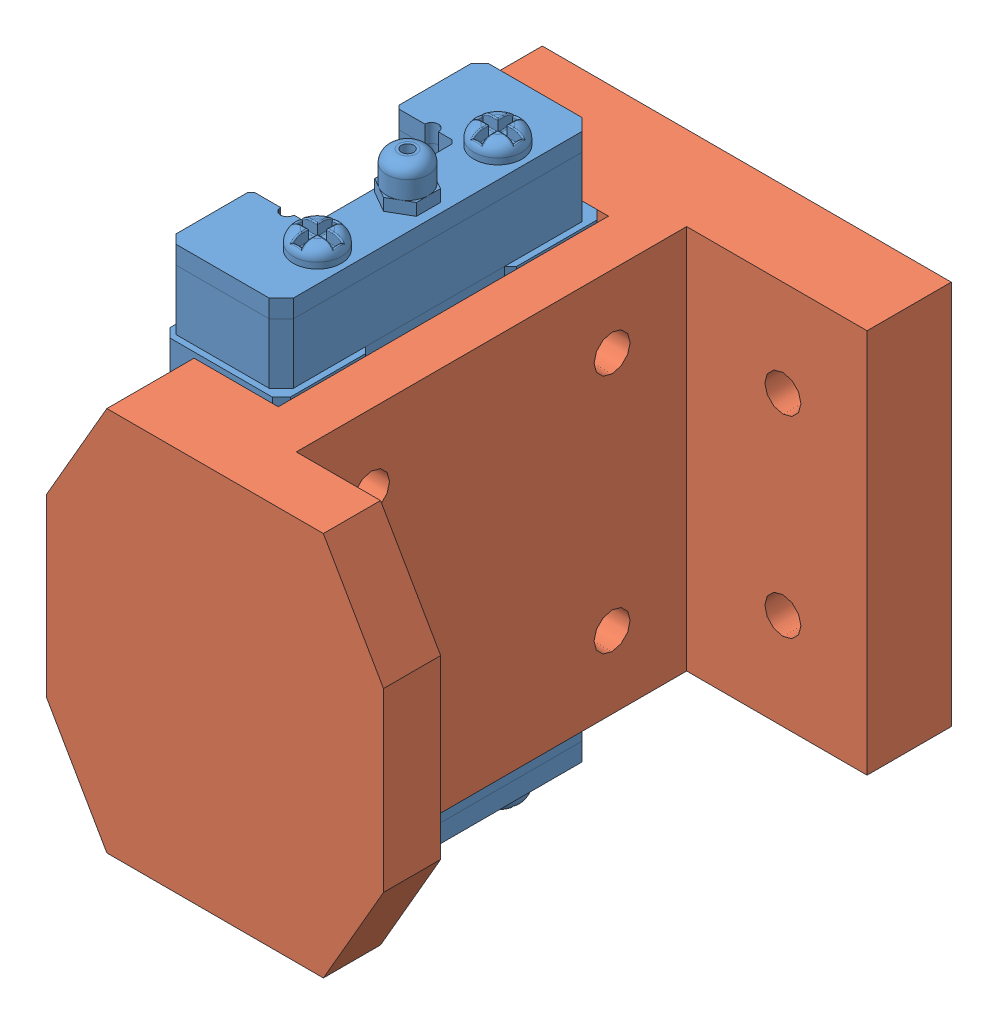
SolidWorks assembly Ползун с зажимом зеркально 2, configuration По умолчанию. Lengths in mm.
Overall size (34 50.47 44.2).
2 component instances, 2 part files, 6 mates.
Components (placement in the parent):
- Ползун-1: Ползун [Default] at (-13 6.5 0) x (0 0 1) z (0 1 0) size (27 10 50.47)
- Тавр обрезаный-2: Тавр обрезаный [По умолчанию] at (0 38.7 -18) x (0 0 1) z (1 0 0) size (44.2 32 34)
Mates (geometry in assembly coordinates):
- Совпадение1: coincident anti-aligned: plane of Ползун-1 through (-7 0 6) normal (0 -1 0); plane of assembly through (0 0 0) normal (0 1 0)
- Совпадение2: coincident aligned: plane of Ползун-1 through (0 38.9 -13.5) normal (1 0 0); plane of assembly through (0 0 0) normal (1 0 0)
- Совпадение3: coincident anti-aligned: plane of Ползун-1; plane of assembly through (0 0 0) normal (0 0 1)
- Concentric6: concentric: cylinder of Ползун-1 through (0 12.7 10) axis (1 0 0) radius 1.25; cylinder of Тавр обрезаный-2 through (27.0125 12.7 10) axis (-1 0 0) radius 1.5
- Concentric7: concentric: cylinder of Ползун-1 through (0 32.7 -10) axis (1 0 0) radius 1.25; cylinder of Тавр обрезаный-2 through (27.0125 32.7 -10) axis (-1 0 0) radius 1.5
- Coincident2: coincident anti-aligned: plane of Ползун-1 through (0 38.9 -13.5) normal (1 0 0); plane of Тавр обрезаный-2 through (0 38.7 -18) normal (-1 0 0)
